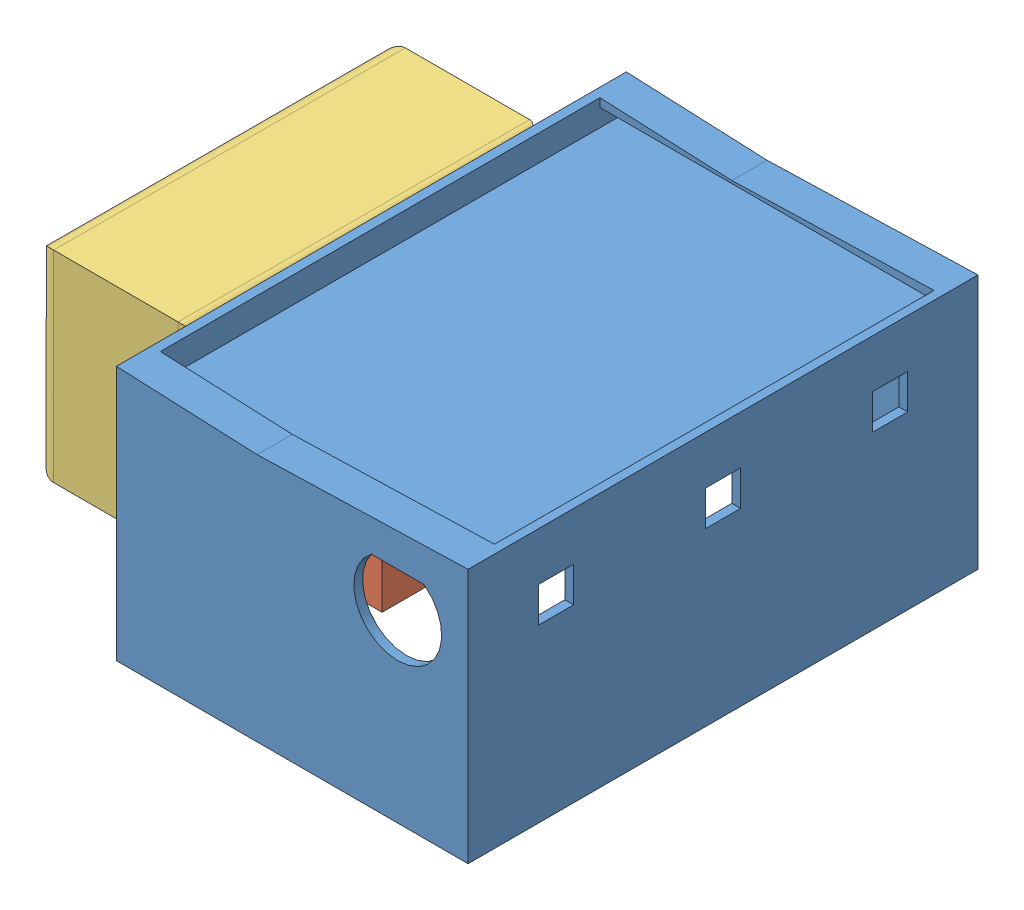
SolidWorks assembly Encloser Ass, configuration Default. Lengths in mm.
Overall size (290.73 145 290).
6 component instances, 6 part files, 5 mates.
Components (placement in the parent):
- Encloser Bottom-2: Encloser Bottom [Default] at (220.5767 -18.3705 -54.4786) size (200 145 290)
- Charge Controller-2: Charge Controller [Default] at (187.2818 76.6295 124.0521) size (134 35 70)
- Inverter-1: Inverter [Default] at (122.015 64.8164 33.4926) x (0 0.001955 0.999998) z (0 -0.999998 0.001955) size (226.36 90.72 114.3)
- PCB Stack-1: PCB Stack [Default] at (161.8296 60.8295 -81.2839) size (115 50.8 68)
- Motor Power-2: Motor Power [Default] at (227.6175 109.6295 62.7808) x (0.017561 0 -0.999846) z (0.999846 0 0.017561) size (62.09 14 27.5)
- Wire Splitter-2: Wire Splitter [Default] at (293.0029 103.664 45.7378) x (0.015911 0 -0.999873) z (0 1 0) size (33.65 41.4 14.7)
Mates (geometry in assembly coordinates):
- Coincident2: coincident: plane of Encloser Bottom-2 through (319.515 111.6295 178.4153) normal (0 -1 0); line of Charge Controller-2 through (266.2225 111.6295 99.0126) axis (-1 0 0)
- Coincident3: coincident anti-aligned: plane of Encloser Bottom-2 through (124.515 -8.3705 -111.5847) normal (-1 0 0); plane of Inverter-1 through (124.515 95.7864 -67.9281) normal (1 0 0)
- Coincident4: coincident: plane of Encloser Bottom-2 through (319.515 111.6295 178.4153) normal (0 -1 0); line of PCB Stack-1 through (136.7808 111.6295 -35.9668) axis (1 0 0)
- Coincident6: coincident anti-aligned: plane of Encloser Bottom-2 through (319.515 111.6295 178.4153) normal (0 -1 0); plane of Motor Power-2 through (228.9722 111.6295 27.1876) normal (0 1 0)
- Coincident9: coincident anti-aligned: plane of Encloser Bottom-2 through (319.515 111.6295 178.4153) normal (0 -1 0); plane of Wire Splitter-2 through (269.9413 111.6295 55.7114) normal (0 1 0)
